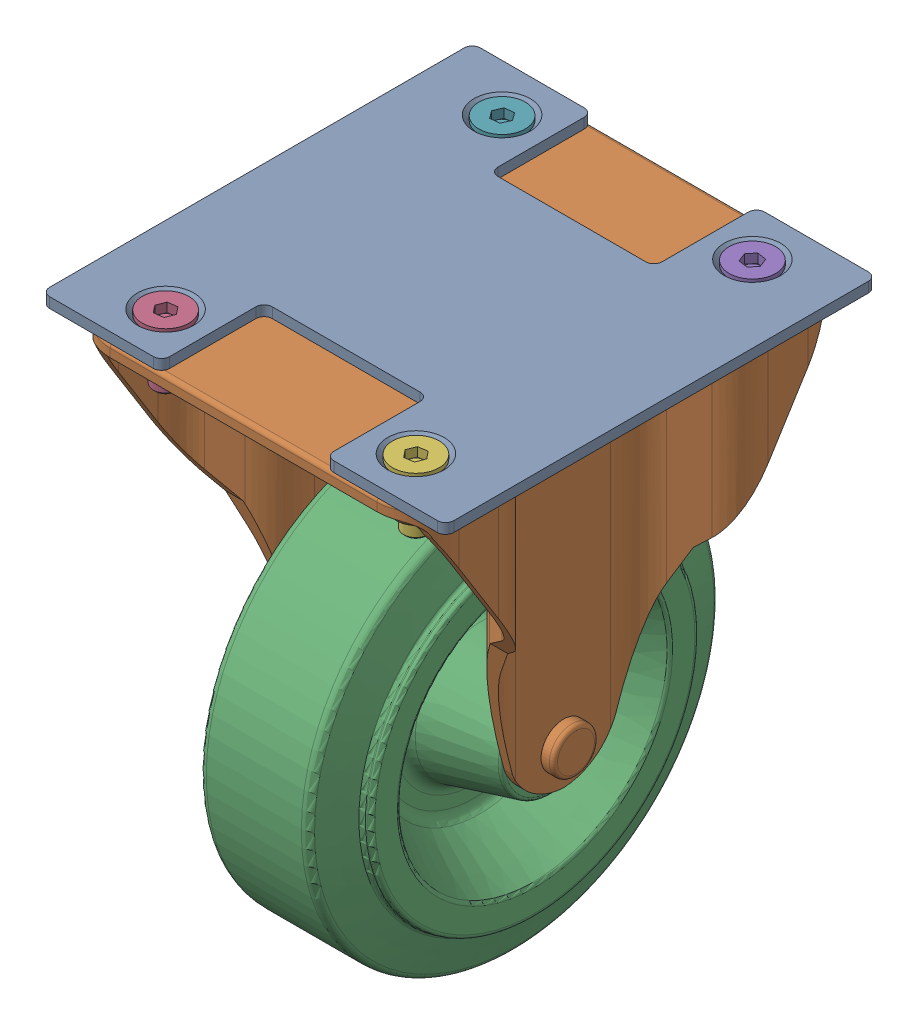
SolidWorks assembly TR23-RC-0600, configuration Default. Lengths in mm.
Overall size (98.5 146.76 124.53).
16 component instances, 6 part files, 0 mates.
Components (placement in the parent):
- TR23-RC-0045-1: TR23-RC-0045 [Default] x (0 0 -1) z (1 0 0) size (105 2.5 98.5)
- 99999-004-01-00-1: 99999-004-01-00 [Default] at (42.5 0 0) x (0 0 -1) z (1 0 0) size (124.53 144.27 85)
  - 99999-004-01-02-1: 99999-004-01-02 [Default] at origin size (105 91 85)
  - 99999-004-01-01-1: 99999-004-01-01 [Default] at (0 -82 -42.5) x (0 0 -1) z (-0.287519 0.957775 0) size (47 100 100)
- ISO 10642 socket countersunk head screw_ISO 10642 - M6 x 16 - 16N-1: ISO 10642 socket countersunk head screw_ISO 10642 - M6 x 16 - 16N [Default] at (-30.5 2.365 41) x (0 -1 0) z (-0.78832 0 0.615266) size (16 11.34 11.34)
- ISO 10642 socket countersunk head screw_ISO 10642 - M6 x 16 - 16N-2: ISO 10642 socket countersunk head screw_ISO 10642 - M6 x 16 - 16N [Default] at (30.5 2.365 -41) x (0 -1 0) z (-0.153736 0 0.988112) size (16 11.34 11.34)
- ISO 10642 socket countersunk head screw_ISO 10642 - M6 x 16 - 16N-3: ISO 10642 socket countersunk head screw_ISO 10642 - M6 x 16 - 16N [Default] at (30.5 2.365 41) x (0 -1 0) z (0.157029 0 0.987594) size (16 11.34 11.34)
- ISO 10642 socket countersunk head screw_ISO 10642 - M6 x 16 - 16N-4: ISO 10642 socket countersunk head screw_ISO 10642 - M6 x 16 - 16N [Default] at (-30.5 2.365 -41) x (0 -1 0) z (0.108107 0 0.994139) size (16 11.34 11.34)
- ISO 7093 M6 Large Washer-1: ISO 7093 M6 Large Washer [Default] at (30.5 -2.8 -41) size (18 1.6 18)
- ISO 7093 M6 Large Washer-2: ISO 7093 M6 Large Washer [Default] at (-30.5 -2.8 -41) x (-0.999992 0 0.004033) z (0.004033 0 0.999992) size (18 1.6 18)
- ISO 7093 M6 Large Washer-3: ISO 7093 M6 Large Washer [Default] at (-30.5 -2.8 41) x (-0.193285 0 -0.981143) z (0.981143 0 -0.193285) size (18 1.6 18)
- ISO 7093 M6 Large Washer-4: ISO 7093 M6 Large Washer [Default] at (30.5 -2.8 41) x (-0.837169 0 -0.546944) z (0.546944 0 -0.837169) size (18 1.6 18)
- ISO 10511 M6 Locking Nut-1: ISO 10511 M6 Locking Nut [Default] at (-30.5 -3.6 -41) x (1 0 0) z (0 0 -1) size (10 6 11.55)
- ISO 10511 M6 Locking Nut-2: ISO 10511 M6 Locking Nut [Default] at (30.5 -3.6 -41) x (1 0 0) z (0 0 -1) size (10 6 11.55)
- ISO 10511 M6 Locking Nut-3: ISO 10511 M6 Locking Nut [Default] at (30.5 -3.6 41) x (0.933518 0 0.358532) z (0.358532 0 -0.933518) size (10 6 11.55)
- ISO 10511 M6 Locking Nut-4: ISO 10511 M6 Locking Nut [Default] at (-30.5 -3.6 41) x (0.193285 0 0.981143) z (0.981143 0 -0.193285) size (10 6 11.55)
